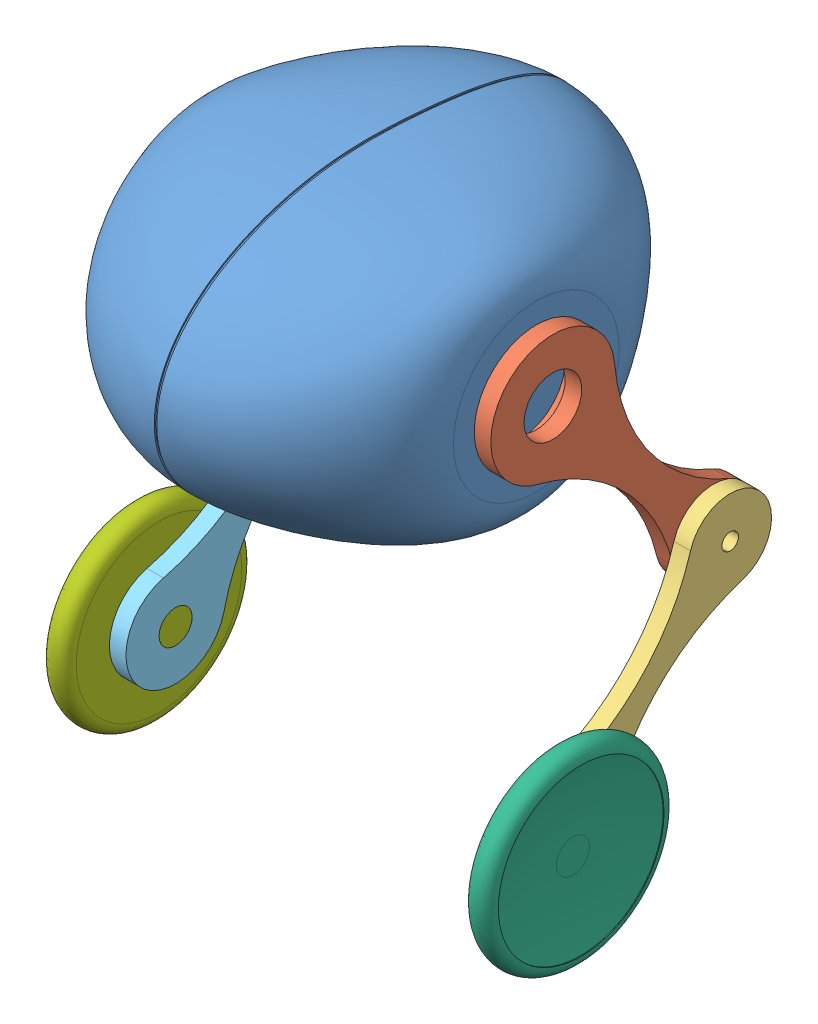
SolidWorks assembly two_wheel_bot, configuration Default. Lengths in mm.
Overall size (270 391.49 282.66).
7 component instances, 7 part files, 17 mates.
Components (placement in the parent):
- body-1: body [Default] at origin size (200.01 191.98 277.19)
- link1L-1: link1L [Default] at (100 0 0) x (1 0 0) z (0 -0.647523 0.762046) size (20 212.5 75)
- link4_1L-3: link4_1L [Default] at (110 -57.1903 -153.1436) x (1 0 0) z (0 0.700189 0.713957) size (20 205 60)
- link1R-1: link1R [Default] at (-100 0 0) x (-1 0 0) z (0 0.647523 -0.762046) size (20 212.5 75)
- link4_1R-2: link4_1R [Default] at (-110 -57.1903 -153.1436) x (-1 0 0) z (0 -0.700189 -0.713957) size (20 205 60)
- wheelL-1: wheelL [Default] at (125 -221.4005 7.8999) x (1 0 0) z (0 -0.359363 -0.933198) size (25 115 115)
- wheelR-1: wheelR [Default] at (-125 -221.4005 7.8999) x (-1 0 0) z (0 -1 0) size (25 115 115)
Mates (geometry in assembly coordinates):
- Coincident2: coordinate: unknown of body-1
- Concentric1: concentric anti-aligned: cylinder of body-1 through (90 0 0) axis (1 0 0) radius 37.5; cylinder of link1L-1 through (110 0 0) axis (-1 0 0) radius 37.5
- Coincident3: coincident anti-aligned: plane of body-1 through (90 0 0) normal (1 0 0); plane of link1L-1 through (90 0 0) normal (-1 0 0)
- Concentric5: concentric anti-aligned: cylinder of link1L-1 through (110 -114.3069 -97.1285) axis (-1 0 0) radius 15; cylinder of link4_1L-3 through (100 -114.3069 -97.1285) axis (1 0 0) radius 15
- Coincident6: coincident anti-aligned: plane of link1L-1 through (110 0 0) normal (1 0 0); plane of link4_1L-3 through (110 -57.1903 -153.1436) normal (-1 0 0)
- Concentric6: concentric anti-aligned: cylinder of body-1 through (-90 0 0) axis (-1 0 0) radius 37.5; cylinder of link1R-1 through (-110 0 0) axis (1 0 0) radius 37.5
- Coincident8: coincident anti-aligned: plane of body-1 through (-90 0 0) normal (-1 0 0); plane of link1R-1 through (-90 0 0) normal (1 0 0)
- Coincident11: coincident anti-aligned: plane of link1R-1 through (-110 0 0) normal (-1 0 0); plane of link4_1R-2 through (-110 -57.1903 -153.1436) normal (1 0 0)
- Concentric10: concentric anti-aligned: cylinder of link1R-1 through (-110 -114.3069 -97.1285) axis (1 0 0) radius 15; cylinder of link4_1R-2 through (-100 -114.3069 -97.1285) axis (-1 0 0) radius 15
- Concentric11: concentric anti-aligned: cylinder of link4_1L-3 through (120 -221.4005 7.8999) axis (-1 0 0) radius 10; cylinder of wheelL-1 through (110 -221.4005 7.8999) axis (1 0 0) radius 10
- Coincident13: coincident anti-aligned: plane of link4_1L-3 through (120 -57.1903 -153.1436) normal (1 0 0); plane of wheelL-1 through (120 -221.4005 7.8999) normal (-1 0 0)
- Concentric12: concentric anti-aligned: cylinder of link4_1R-2 through (-120 -221.4005 7.8999) axis (1 0 0) radius 10; cylinder of wheelR-1 through (-110 -221.4005 7.8999) axis (-1 0 0) radius 10
- Coincident14: coincident anti-aligned: plane of link4_1R-2 through (-120 -57.1903 -153.1436) normal (-1 0 0); plane of wheelR-1 through (-120 -221.4005 7.8999) normal (1 0 0)
- Concentric14: concentric anti-aligned: cylinder of link4_1L-3 through (120 -221.4005 7.8999) axis (-1 0 0) radius 30; cylinder of link4_1R-2 through (-120 -221.4005 7.8999) axis (1 0 0) radius 30
- Perpendicular2: perpendicular: unknown of link4_1L-1; unknown of wheelL-1
- Perpendicular1: perpendicular: unknown of link4_1L-2; plane of wheelR-1 through (-125 -210.1531 95.4054) normal (0 -1 0)
- Parallel3: parallel anti-aligned: plane of body-1 through (0 0 0) normal (0 0 1); plane of link4_1L-1
